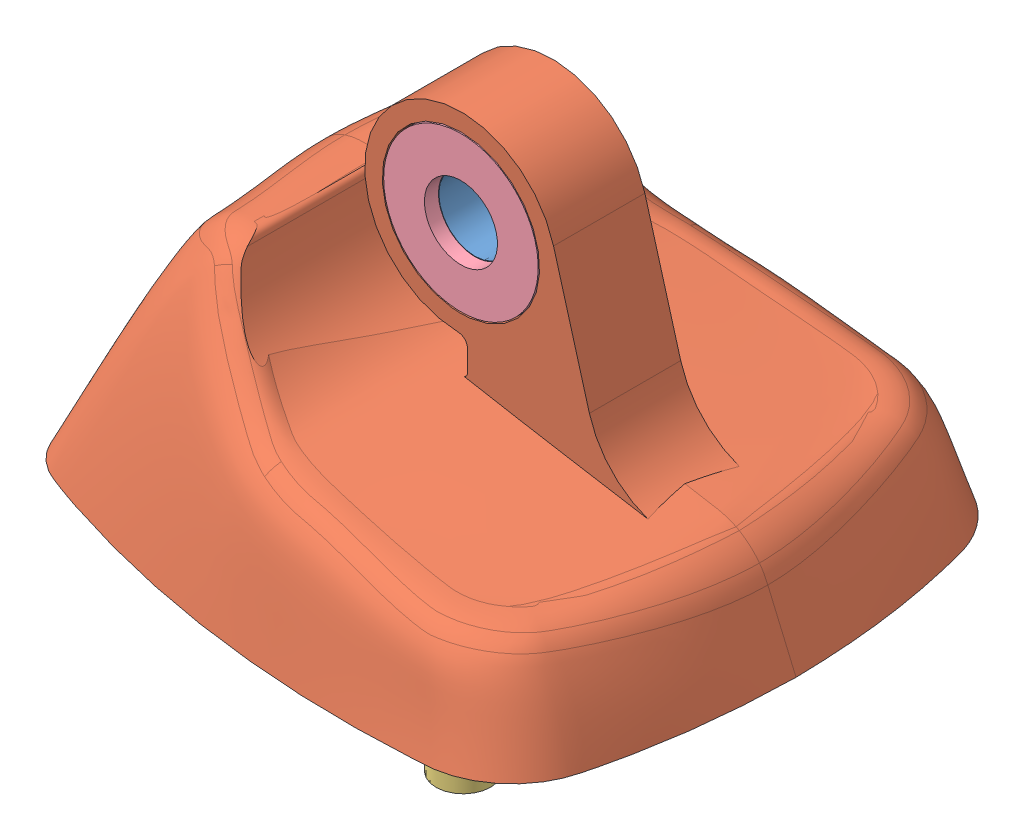
SolidWorks assembly DownAssem, configuration Default. Lengths in mm.
Overall size (42.09 43.85 37.33).
6 component instances, 6 part files, 12 mates.
Components (placement in the parent):
- base metal-1: base metal [Default] at (-19.3424 -0.4283 1.3444) size (26 19.8 16.8)
- base_plastic_4-1: base_plastic_4 [Default] at (1897.0017 -6209.6505 23.1132) x (-1 0 0) z (0 -1 0) size (42533.26 37922.71 43425.84)
- BaseScrew-1: BaseScrew [Default] at (-19.3276 1.1717 1.3444) x (0.874553 0 0.484931) z (-0.484931 0 0.874553) size (10.39 25.7 9)
- ThinMetalWasher-1: ThinMetalWasher [Default] at (-16.2424 13.8717 3.5944) size (11 11 1)
- ThickMetalWasher-1: ThickMetalWasher [Default] at (-16.2424 13.8717 -2.0056) size (11 11 1.1)
- washer-1: washer [Default] at (-19.3276 -0.5158 1.3444) x (0 0 1) z (1 0 0) size (21 4 21)
Mates (geometry in assembly coordinates):
- Concentric1: concentric anti-aligned: cylinder of base metal-1 through (-16.2424 13.8717 3.5944) axis (0 0 -1) radius 2.575; cylinder of base_plastic_4-1 through (-16.2424 13.8717 -1.9056) axis (0 0 1) radius 5.6
- Distance2: distance = 1 mm aligned: plane of base_plastic_4-1 through (-15.3768 -4.0158 4.5944) normal (0 0 1); plane of base metal-1 through (-19.3424 -0.4283 3.5944) normal (0 0 1)
- Concentric3: concentric aligned: cylinder of base_plastic_4-1 through (-19.3276 -8.0158 1.3444) axis (0 1 0) radius 2.75; cylinder of BaseScrew-1 through (-19.3276 -23.1283 1.3444) axis (0 1 0) radius 2.5
- Parallel1: parallel anti-aligned: plane of base metal-1 through (-14.6842 1.0217 1.2637) normal (-0.99985 0 0.017314); plane of BaseScrew-1 through (-14.7843 2.5717 3.8636) normal (0.99985 0 -0.017314)
- Coincident3: coincident anti-aligned: plane of base metal-1 through (-19.3424 2.5717 1.3444) normal (0 -1 0); plane of BaseScrew-1 through (-19.3276 2.5717 1.3444) normal (0 1 0)
- Concentric4: concentric aligned: cylinder of base metal-1 through (-16.2424 13.8717 3.5944) axis (0 0 -1) radius 2.575; cylinder of ThickMetalWasher-1 through (-16.2424 13.8717 -0.9056) axis (0 0 -1) radius 2.6
- Coincident4: coincident anti-aligned: plane of base metal-1 through (-19.3424 -0.4283 -0.9056) normal (0 0 -1); plane of ThickMetalWasher-1 through (-16.2424 13.8717 -0.9056) normal (0 0 1)
- Concentric5: concentric anti-aligned: cylinder of base metal-1 through (-16.2424 13.8717 3.5944) axis (0 0 -1) radius 2.575; circle of ThinMetalWasher-1
- Coincident5: coincident anti-aligned: plane of base metal-1 through (-19.3424 -0.4283 3.5944) normal (0 0 1); plane of ThinMetalWasher-1 through (-16.2424 13.8717 3.5944) normal (0 0 -1)
- Coincident6: coincident anti-aligned: plane of base_plastic_4-1 through (-15.3768 -0.5158 1.3444) normal (0 -1 0); plane of washer-1 through (-19.3276 -0.5158 1.3444) normal (0 1 0)
- Concentric6: concentric aligned: cylinder of base_plastic_4-1 through (-19.3276 -4.0158 1.3444) axis (0 1 0) radius 4.95; cylinder of washer-1 through (-19.3276 -17.2731 1.3444) axis (0 1 0) radius 3.65
- Parallel3: parallel aligned: plane of base metal-1 through (-19.3424 -0.4283 1.3444) normal (0 0 1); plane of washer-1
